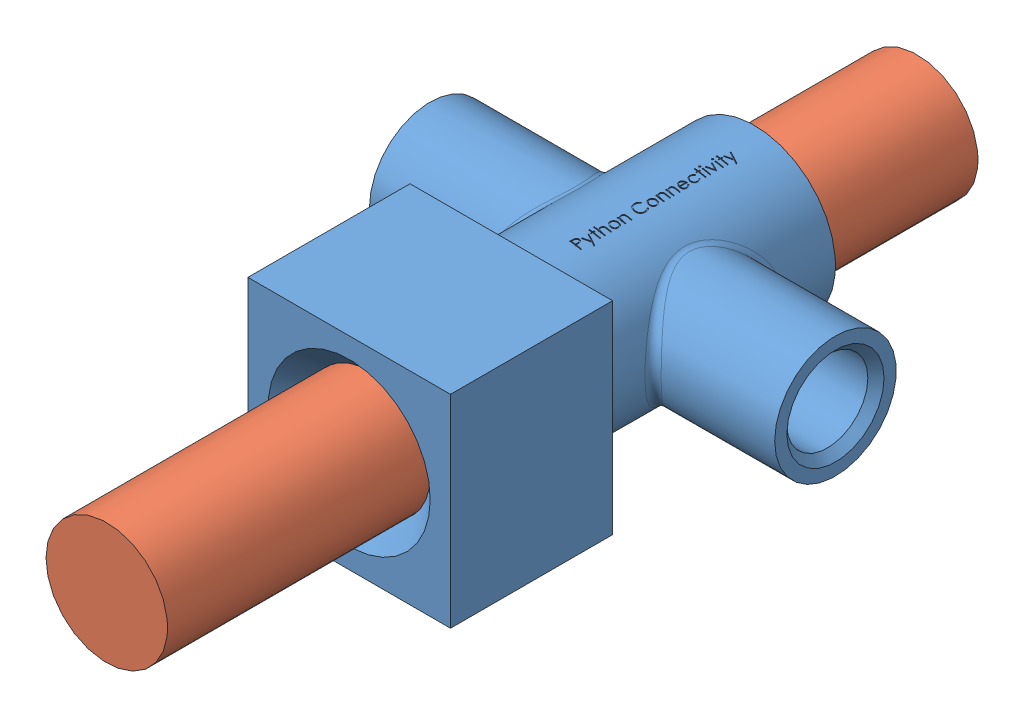
SolidWorks assembly Assem1, configuration Default. Lengths in mm.
Overall size (127 63.5 254).
2 component instances, 2 part files, 1 mates.
Components (placement in the parent):
- Valve-1: Valve [Default] at (37.067 76.1514 32.7295) size (127 63.5 127)
- Valve_Rod-1: Valve_Rod [Default] at (37.067 76.1514 -18.2944) size (38.1 38.1 254)
Mates (geometry in assembly coordinates):
- Concentric1: concentric: cylinder of Valve-1 through (37.067 76.1514 159.7295) axis (0 0 -1) radius 19.05; cylinder of Valve_Rod-1 through (37.067 76.1514 235.7056) axis (0 0 -1) radius 19.05
